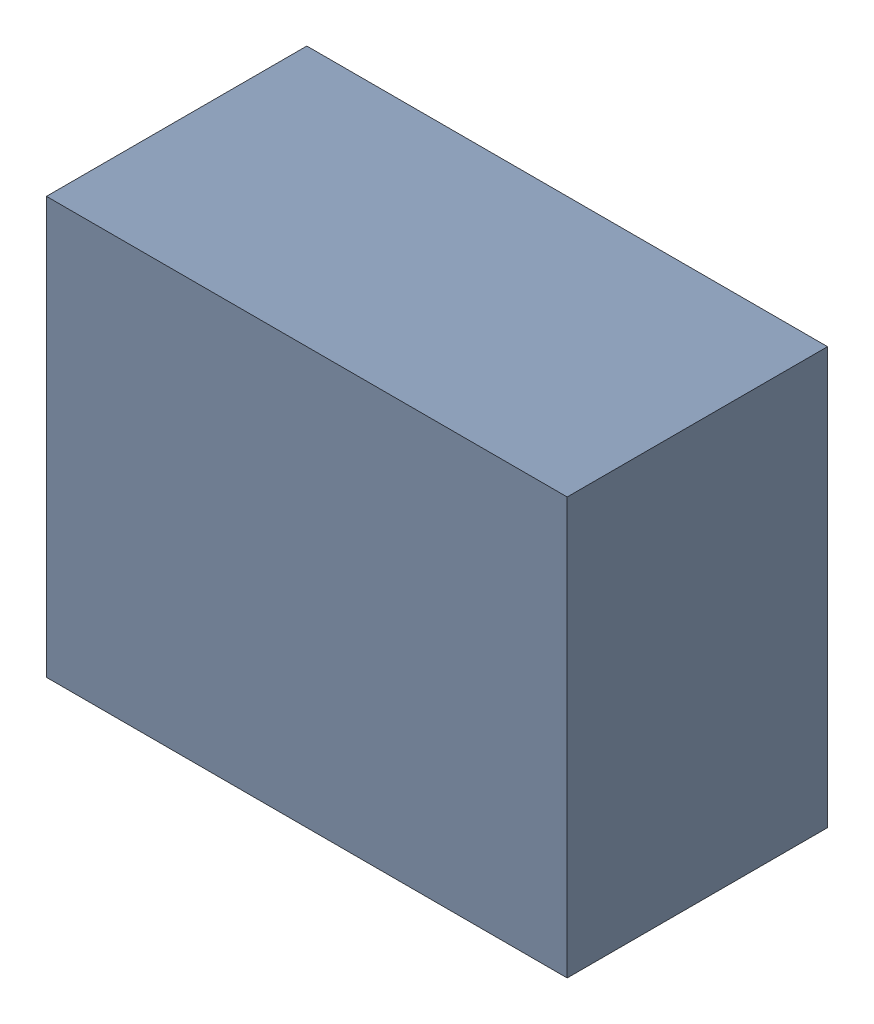
SolidWorks assembly D7, configuration Default. Lengths in mm.
Overall size (1 0.8 0.5).
2 component instances, 1 part files, 0 mates.
Components (placement in the parent):
- 870940960-1: 870940960 [Default] at (74.4974 43.1524 0) size (1 0.8 0.5)
  - Extruded_33-1: Extruded_33 [Default] at origin size (1 0.8 0.5)
